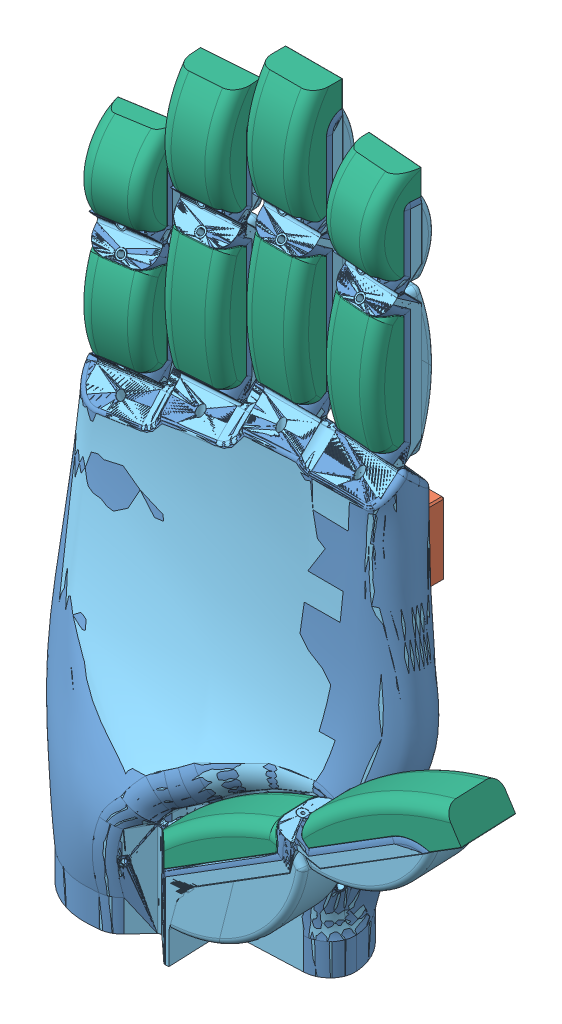
SolidWorks assembly HandAssembly2, configuration Default. Lengths in mm.
Overall size (153.67 227.4 65.46).
29 component instances, 6 part files, 43 mates.
Components (placement in the parent):
- Hand-1: Hand [Default] at origin size (147.59 222.67 61.95)
- ServoAssem-1: ServoAssem [Default] at (17.11 -26.63 -24.3814) x (1 0 0) z (0 -1 0) size (13.78 32.4 32)
  - AGFRC Micro Servo-1: AGFRC Micro Servo [Default] at origin size (12 31.6 32)
  - Pulley-1: Pulley [Default] at (0 28.4 5.5) x (1 0 0) z (0 -1 0) size (13.78 13.78 4)
- ServoAssem-2: ServoAssem [Default] at (-4 -49.63 -24.3814) x (-1 0 0) z (0 1 0) size (13.78 32.4 32)
  - AGFRC Micro Servo-1: AGFRC Micro Servo [Default] at origin size (12 31.6 32)
  - Pulley-1: Pulley [Default] at (0 28.4 5.5) x (1 0 0) z (0 -1 0) size (13.78 13.78 4)
- ServoAssem-3: ServoAssem [Default] at (-20.229 -26.63 -24.3814) x (1 0 0) z (0 -1 0) size (13.78 32.4 32)
  - AGFRC Micro Servo-1: AGFRC Micro Servo [Default] at origin size (12 31.6 32)
  - Pulley-1: Pulley [Default] at (0 28.4 5.5) x (1 0 0) z (0 -1 0) size (13.78 13.78 4)
- ServoAssem-4: ServoAssem [Default] at (-38.46 -26.63 -24.3814) x (1 0 0) z (0 -1 0) size (13.78 32.4 32)
  - AGFRC Micro Servo-1: AGFRC Micro Servo [Default] at origin size (12 31.6 32)
  - Pulley-1: Pulley [Default] at (0 28.4 5.5) x (1 0 0) z (0 -1 0) size (13.78 13.78 4)
- ServoAssem-6: ServoAssem [Default] at (1.5 -77.13 -24.3814) x (0 -1 0) z (-1 0 0) size (13.78 32.4 32)
  - AGFRC Micro Servo-1: AGFRC Micro Servo [Default] at origin size (12 31.6 32)
  - Pulley-1: Pulley [Default] at (0 28.4 5.5) x (1 0 0) z (0 -1 0) size (13.78 13.78 4)
- ServoAssem-7: ServoAssem [Default] at (1.4 -114.356 -2.7814) x (0 0 -1) z (0 1 0) size (13.78 32.4 32)
  - AGFRC Micro Servo-1: AGFRC Micro Servo [Default] at origin size (12 31.6 32)
  - Pulley-1: Pulley [Default] at (0 28.4 5.5) x (1 0 0) z (0 -1 0) size (13.78 13.78 4)
- SensorPCB-1: SensorPCB [Default] at (25.2355 63.12 -1.7931) x (0.996917 0 0.078459) z (0 -1 0) size (12.4 3.2 10.5)
- SensorPCB-2: SensorPCB [Default] at (25.2355 23.12 -1.7931) x (0.996917 0 0.078459) z (0 -1 0) size (12.4 3.2 10.5)
- SensorPCB-6: SensorPCB [Default] at (0 70.75 -1.6) x (1 0 0) z (0 -1 0) size (12.4 3.2 10.5)
- SensorPCB-8: SensorPCB [Default] at (0 25.5 -1.6) x (1 0 0) z (0 -1 0) size (12.4 3.2 10.5)
- SensorPCB-10: SensorPCB [Default] at (-24.3431 60.45 0.1261) x (0.997453 0 -0.071323) z (0 -1 0) size (12.4 3.2 10.5)
- SensorPCB-12: SensorPCB [Default] at (-24.7221 10.21 0.1532) x (-0.997453 0 0.071323) z (0 1 0) size (12.4 3.2 10.5)
- SensorPCB-14: SensorPCB [Default] at (-46.7194 41.62 3.7142) x (0.986771 0 -0.162121) z (0 -1 0) size (12.4 3.2 10.5)
- SensorPCB-16: SensorPCB [Default] at (-46.7194 7.27 3.7142) x (0.986771 0 -0.162121) z (0 -1 0) size (12.4 3.2 10.5)
- RidgedBackPlates-1: RidgedBackPlates [Default] at origin size (147.59 222.67 61.95)
- SquishyFrontPieces-1: SquishyFrontPieces [Default] at origin size (143.98 202.57 46.2)
Mates (geometry in assembly coordinates):
- Width1: width anti-aligned: plane of Hand-1 through (23.61 -50.13 46.9567) normal (-1 0 0); plane of ServoAssem-1/AGFRC Micro Servo-1 through (10.61 -50.13 46.9567) normal (1 0 0); plane of Hand-1 through (23.11 -26.63 -24.3814) normal (1 0 0); plane of ServoAssem-1/AGFRC Micro Servo-1 through (11.11 -26.63 -24.3814) normal (-1 0 0)
- Width2: width aligned: plane of Hand-1 through (23.61 -50.13 46.9567) normal (0 1 0); plane of ServoAssem-1/AGFRC Micro Servo-1 through (10.61 -26.13 46.9567) normal (0 -1 0); plane of Hand-1 through (23.11 -26.63 -24.3814) normal (0 1 0); plane of ServoAssem-1/AGFRC Micro Servo-1 through (23.11 -49.63 -24.3814) normal (0 -1 0)
- Coincident1: coincident anti-aligned: plane of Hand-1 through (0 0 -2.4814) normal (0 0 -1); plane of ServoAssem-1/AGFRC Micro Servo-1 through (23.11 -26.63 -2.4814) normal (0 0 1)
- Width3: width anti-aligned: plane of Hand-1 through (-10.5 -50.13 46.9567) normal (1 0 0); plane of ServoAssem-2/AGFRC Micro Servo-1 through (2.5 -50.13 46.9567) normal (-1 0 0); plane of Hand-1 through (-10 -49.63 -24.3814) normal (-1 0 0); plane of ServoAssem-2/AGFRC Micro Servo-1 through (2 -49.63 -24.3814) normal (1 0 0)
- Width4: width aligned: plane of Hand-1 through (2.5 -50.13 46.9567) normal (0 1 0); plane of ServoAssem-2/AGFRC Micro Servo-1 through (2.5 -26.13 46.9567) normal (0 -1 0); plane of Hand-1 through (-10 -49.63 -24.3814) normal (0 -1 0); plane of ServoAssem-2/AGFRC Micro Servo-1 through (-10 -26.63 -24.3814) normal (0 1 0)
- Coincident2: coincident anti-aligned: plane of Hand-1 through (0 0 -2.4814) normal (0 0 -1); plane of ServoAssem-2/AGFRC Micro Servo-1 through (-10 -49.63 -2.4814) normal (0 0 1)
- Coincident3: coincident anti-aligned: plane of Hand-1 through (0 0 -2.4814) normal (0 0 -1); plane of ServoAssem-3/AGFRC Micro Servo-1 through (-14.229 -26.63 -2.4814) normal (0 0 1)
- Width5: width anti-aligned: plane of Hand-1 through (-26.729 -50.13 46.9567) normal (1 0 0); plane of ServoAssem-3/AGFRC Micro Servo-1 through (-13.729 -50.13 46.9567) normal (-1 0 0); plane of Hand-1 through (-14.229 -26.63 -24.3814) normal (1 0 0); plane of ServoAssem-3/AGFRC Micro Servo-1 through (-26.229 -26.63 -24.3814) normal (-1 0 0)
- Width6: width aligned: plane of Hand-1 through (-13.729 -50.13 46.9567) normal (0 1 0); plane of ServoAssem-3/AGFRC Micro Servo-1 through (-13.729 -26.13 46.9567) normal (0 -1 0); plane of Hand-1 through (-14.229 -26.63 -24.3814) normal (0 1 0); plane of ServoAssem-3/AGFRC Micro Servo-1 through (-14.229 -49.63 -24.3814) normal (0 -1 0)
- Coincident4: coincident anti-aligned: plane of Hand-1 through (0 0 -2.4814) normal (0 0 -1); plane of ServoAssem-4/AGFRC Micro Servo-1 through (-32.46 -26.63 -2.4814) normal (0 0 1)
- Width7: width anti-aligned: plane of Hand-1 through (-44.96 -50.13 46.9567) normal (1 0 0); plane of ServoAssem-4/AGFRC Micro Servo-1 through (-31.96 -26.13 46.9567) normal (-1 0 0); plane of Hand-1 through (-32.46 -26.63 -24.3814) normal (1 0 0); plane of ServoAssem-4/AGFRC Micro Servo-1 through (-44.46 -26.63 -24.3814) normal (-1 0 0)
- Width8: width aligned: plane of Hand-1 through (-31.96 -50.13 46.9567) normal (0 1 0); plane of ServoAssem-4/AGFRC Micro Servo-1 through (-31.96 -26.13 46.9567) normal (0 -1 0); plane of Hand-1 through (-32.46 -26.63 -24.3814) normal (0 1 0); plane of ServoAssem-4/AGFRC Micro Servo-1 through (-32.46 -49.63 -24.3814) normal (0 -1 0)
- Width13: width anti-aligned: plane of Hand-1 through (2 -83.63 46.9567) normal (0 1 0); plane of ServoAssem-6/AGFRC Micro Servo-1 through (-22 -70.63 46.9567) normal (0 -1 0); plane of Hand-1 through (1.5 -83.13 -24.3814) normal (0 -1 0); plane of ServoAssem-6/AGFRC Micro Servo-1 through (1.5 -71.13 -24.3814) normal (0 1 0)
- Width14: width aligned: plane of Hand-1 through (-22 -83.63 46.9567) normal (1 0 0); plane of ServoAssem-6/AGFRC Micro Servo-1 through (2 -83.63 46.9567) normal (-1 0 0); plane of Hand-1 through (1.5 -83.13 -24.3814) normal (1 0 0); plane of ServoAssem-6/AGFRC Micro Servo-1 through (-21.5 -83.13 -24.3814) normal (-1 0 0)
- Coincident6: coincident anti-aligned: plane of Hand-1 through (0 0 -2.4814) normal (0 0 -1); plane of ServoAssem-6/AGFRC Micro Servo-1 through (1.5 -83.13 -2.4814) normal (0 0 1)
- Width16: width aligned: plane of Hand-1 through (1.9 -90.856 46.9567) normal (-1 0 0); plane of ServoAssem-7/AGFRC Micro Servo-1 through (-26.5 -128.856 -0.4814) normal (1 0 0); plane of Hand-1 through (-26 -114.356 -8.7814) normal (-1 0 0); plane of ServoAssem-7/AGFRC Micro Servo-1 through (1.4 -114.356 -8.7814) normal (1 0 0)
- Parallel1: parallel aligned: plane of Hand-1 through (0 0 -2.4814) normal (0 0 -1); plane of ServoAssem-7/AGFRC Micro Servo-1 through (1.4 -114.356 -8.7814) normal (0 0 -1)
- Coincident7: coincident anti-aligned: plane of Hand-1 through (23.11 -26.63 3.2186) normal (0 0 -1); plane of ServoAssem-7/AGFRC Micro Servo-1 through (1.4 -114.356 3.2186) normal (0 0 1)
- Concentric3: concentric aligned: cylinder of Hand-1 through (-14.2544 -116.856 -6.2814) axis (-1 0 0) radius 0.9; cylinder of ServoAssem-7/AGFRC Micro Servo-1 through (1.4 -116.856 -6.2814) axis (-1 0 0) radius 1.25
- Width18: width aligned: plane of Hand-1 through (19.2105 64.8 -6.6819) normal (0.996917 0 0.078459); plane of SensorPCB-1 through (31.5723 54.3 -5.709) normal (-0.996917 0 -0.078459); plane of Hand-1 through (31.1015 64.8 0.2735) normal (0.996917 0 0.078459); plane of SensorPCB-1 through (18.7397 64.8 -0.6994) normal (-0.996917 0 -0.078459)
- Width19: width anti-aligned: plane of Hand-1 through (19.2105 54.3 -6.6819) normal (0 1 0); plane of SensorPCB-1 through (31.5723 64.8 -5.709) normal (0 -1 0); plane of Hand-1 through (18.7397 54.3 -0.6994) normal (0 -1 0); plane of SensorPCB-1 through (18.7397 64.8 -0.6994) normal (0 1 0)
- Coincident8: coincident anti-aligned: plane of Hand-1 through (-24.0026 -0.88 -4.0632) normal (0.078459 0 -0.996917); plane of SensorPCB-1 through (25.11 63.12 -0.198) normal (-0.078459 0 0.996917)
- Width20: width aligned: plane of Hand-1 through (19.2105 24.8 -6.6819) normal (0.996917 0 0.078459); plane of SensorPCB-2 through (31.5723 14.3 -5.709) normal (-0.996917 0 -0.078459); plane of Hand-1 through (31.1015 24.8 0.2735) normal (0.996917 0 0.078459); plane of SensorPCB-2 through (18.7397 24.8 -0.6994) normal (-0.996917 0 -0.078459)
- Width21: width anti-aligned: plane of Hand-1 through (19.2105 14.3 -6.6819) normal (0 1 0); plane of SensorPCB-2 through (31.5723 24.8 -5.709) normal (0 -1 0); plane of Hand-1 through (18.7397 14.3 -0.6994) normal (0 -1 0); plane of SensorPCB-2 through (18.7397 24.8 -0.6994) normal (0 1 0)
- Coincident9: coincident anti-aligned: plane of Hand-1 through (-24.0026 -0.88 -4.0632) normal (0.078459 0 -0.996917); plane of SensorPCB-2 through (25.11 23.12 -0.198) normal (-0.078459 0 0.996917)
- Width24: width anti-aligned: plane of Hand-1 through (6.01 61.93 -6.001) normal (-1 0 0); plane of SensorPCB-6 through (-6.39 72.43 -6.001) normal (1 0 0); plane of Hand-1 through (6.01 72.43 0) normal (1 0 0); plane of SensorPCB-6 through (-6.39 72.43 0) normal (-1 0 0)
- Width26: width anti-aligned: plane of Hand-1 through (-6.39 61.93 -6.001) normal (0 1 0); plane of SensorPCB-6 through (6.01 72.43 -6.001) normal (0 -1 0); plane of Hand-1 through (-6.39 61.93 0) normal (0 -1 0); plane of SensorPCB-6 through (-6.39 72.43 0) normal (0 1 0)
- Coincident11: coincident anti-aligned: plane of Hand-1 through (-51.3632 0 0) normal (0 0 -1); plane of SensorPCB-6 through (0 70.75 0) normal (0 0 1)
- Width27: width aligned: plane of Hand-1 through (-6.39 27.18 -6.001) normal (1 0 0); plane of SensorPCB-8 through (6.01 16.68 -6.001) normal (-1 0 0); plane of Hand-1 through (6.01 27.18 0) normal (1 0 0); plane of SensorPCB-8 through (-6.39 27.18 0) normal (-1 0 0)
- Width28: width anti-aligned: plane of Hand-1 through (-6.39 16.68 -6.001) normal (0 1 0); plane of SensorPCB-8 through (6.01 27.18 -6.001) normal (0 -1 0); plane of Hand-1 through (-6.39 16.68 0) normal (0 -1 0); plane of SensorPCB-8 through (-6.39 27.18 0) normal (0 1 0)
- Coincident12: coincident anti-aligned: plane of Hand-1 through (-51.3632 0 0) normal (0 0 -1); plane of SensorPCB-8 through (0 25.5 0) normal (0 0 1)
- Width29: width aligned: plane of Hand-1 through (-31.0307 62.13 -3.808) normal (0.997453 0 -0.071323); plane of SensorPCB-10 through (-18.6623 51.63 -4.6924) normal (-0.997453 0 0.071323); plane of Hand-1 through (-18.2343 62.13 1.2933) normal (0.997453 0 -0.071323); plane of SensorPCB-10 through (-30.6027 62.13 2.1778) normal (-0.997453 0 0.071323)
- Width30: width aligned: plane of Hand-1 through (-18.6623 62.13 -4.6924) normal (0 -1 0); plane of SensorPCB-10 through (-31.0307 51.63 -3.808) normal (0 1 0); plane of Hand-1 through (-30.6027 51.63 2.1778) normal (0 -1 0); plane of SensorPCB-10 through (-30.6027 62.13 2.1778) normal (0 1 0)
- Coincident13: coincident anti-aligned: plane of Hand-1 through (-74.2051 -7.25 5.2956) normal (-0.071323 0 -0.997453); plane of SensorPCB-10 through (-24.229 60.45 1.722) normal (0.071323 0 0.997453)
- Width31: width aligned: plane of Hand-1 through (-18.6623 8.53 -4.6924) normal (-0.997453 0 0.071323); plane of SensorPCB-12 through (-31.0307 19.03 -3.808) normal (0.997453 0 -0.071323); plane of Hand-1 through (-30.6027 8.53 2.1778) normal (-0.997453 0 0.071323); plane of SensorPCB-12 through (-18.2343 8.53 1.2933) normal (0.997453 0 -0.071323)
- Width32: width aligned: plane of Hand-1 through (-18.6623 19.03 -4.6924) normal (0 -1 0); plane of SensorPCB-12 through (-31.0307 8.53 -3.808) normal (0 1 0); plane of Hand-1 through (-18.2343 19.03 1.2933) normal (0 1 0); plane of SensorPCB-12 through (-18.2343 8.53 1.2933) normal (0 -1 0)
- Coincident14: coincident anti-aligned: plane of Hand-1 through (-74.2051 -7.25 5.2956) normal (-0.071323 0 -0.997453); plane of SensorPCB-12 through (-24.608 10.21 1.7491) normal (0.071323 0 0.997453)
- Width33: width aligned: plane of Hand-1 through (-53.7384 43.3 0.4073) normal (0.986771 0 -0.162121); plane of SensorPCB-14 through (-41.5024 32.8 -1.603) normal (-0.986771 0 0.162121); plane of Hand-1 through (-40.5295 43.3 4.3187) normal (0.986771 0 -0.162121); plane of SensorPCB-14 through (-52.7655 43.3 6.329) normal (-0.986771 0 0.162121)
- Width34: width aligned: plane of Hand-1 through (-41.5024 43.3 -1.603) normal (0 -1 0); plane of SensorPCB-14 through (-53.7384 32.8 0.4073) normal (0 1 0); plane of Hand-1 through (-52.7655 32.8 6.329) normal (0 -1 0); plane of SensorPCB-14 through (-52.7655 43.3 6.329) normal (0 1 0)
- Coincident15: coincident anti-aligned: plane of Hand-1 through (-88.7388 -12.13 12.2391) normal (-0.162121 0 -0.986771); plane of SensorPCB-14 through (-46.46 41.62 5.293) normal (0.162121 0 0.986771)
- Width35: width aligned: plane of Hand-1 through (-53.7384 8.95 0.4073) normal (0.986771 0 -0.162121); plane of SensorPCB-16 through (-41.5024 -1.55 -1.603) normal (-0.986771 0 0.162121); plane of Hand-1 through (-40.5295 8.95 4.3187) normal (0.986771 0 -0.162121); plane of SensorPCB-16 through (-52.7655 8.95 6.329) normal (-0.986771 0 0.162121)
- Width36: width anti-aligned: plane of Hand-1 through (-53.7384 -1.55 0.4073) normal (0 1 0); plane of SensorPCB-16 through (-41.5024 8.95 -1.603) normal (0 -1 0); plane of Hand-1 through (-52.7655 -1.55 6.329) normal (0 -1 0); plane of SensorPCB-16 through (-52.7655 8.95 6.329) normal (0 1 0)
- Coincident16: coincident anti-aligned: plane of Hand-1 through (-88.7388 -12.13 12.2391) normal (-0.162121 0 -0.986771); plane of SensorPCB-16 through (-46.46 7.27 5.293) normal (0.162121 0 0.986771)
